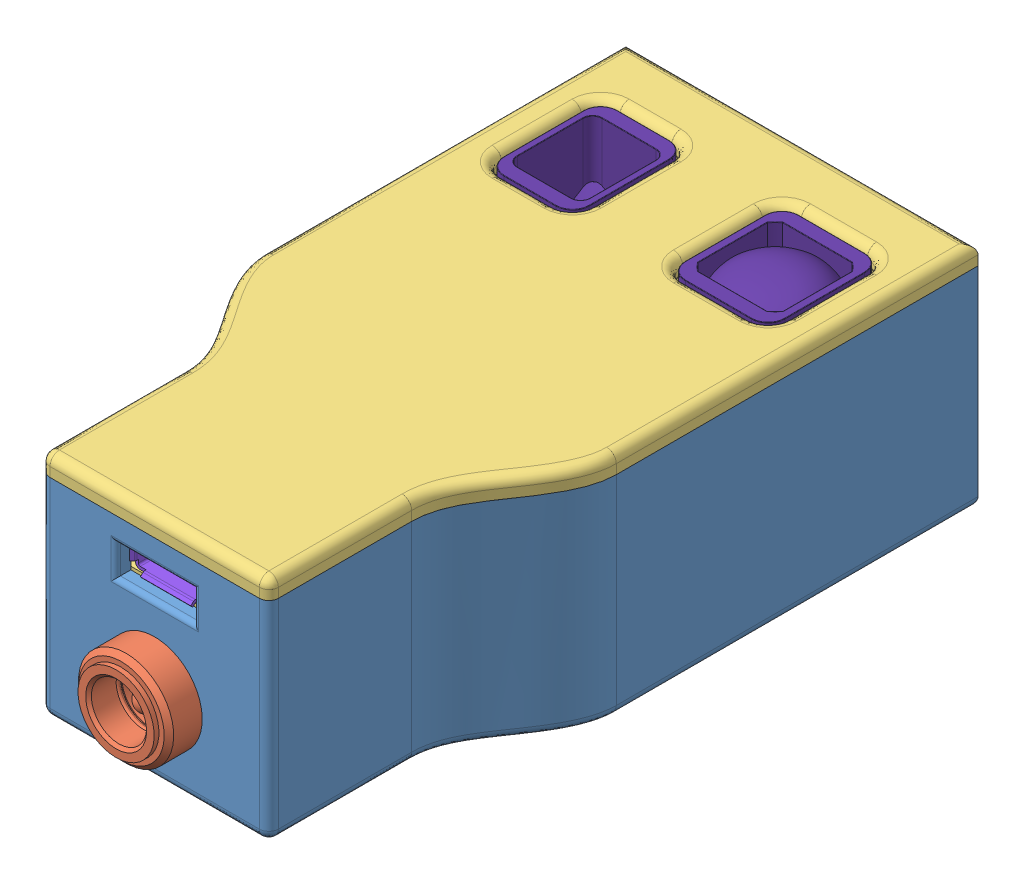
SolidWorks assembly mcu_enclosure, configuration Default. Lengths in mm.
Overall size (39.22 24.22 78.62).
37 component instances, 23 part files, 24 mates.
Components (placement in the parent):
- mcu_enclosure-1: mcu_enclosure [Default] at origin size (38.82 22.11 68)
- Lumberg_1614_10-1: Lumberg_1614_10 [Default] at (0 6 0) x (0 -1 0) z (0 0 1) size (10 10 17.01)
  - Lumberg_1614_10.stp-1: Lumberg_1614_10.stp [Default] at (0.8468 0.2582 0) size (13.42 14.23 17.01)
    - ID_1.stp-1: ID_1.stp [Default] at (-0.8468 -0.2582 0) size (10 10 17.01)
    - ID_1-0.stp-1: ID_1-0.stp [Default] at (-0.8365 -0.3028 -2.0087) x (-0.358368 0.93358 0) z (0 0 1) size (11.4 10 2.51) (hidden)
- 3800 ItsyBitsy M4-1: 3800 ItsyBitsy M4 [Default] at (8.89 13 -1.6) x (0 0 -1) z (0 1 0) size (36.02 17.78 4.34)
  - 3800-ItsyBitsy-M4.step-1: 3800-ItsyBitsy-M4.step [Default] at origin size (36.02 17.78 4.34)
    - PCB Component.step-1: PCB Component.step [Default] at origin size (36.02 17.78 4.34)
      - Board.step-1: Board.step [Default] at origin size (35.56 17.78 1.57)
      - 10_X_B5F.step-1: 10_X_B5F.step [Default] at (12.578 13.375 1.57) size (2 1.25 1)
      - 10_X_B5F.step-2: 10_X_B5F.step [Default] at (8.449 4.176 1.57) x (-1 0 0) z (0 0 1) size (2 1.25 1)
      - 100k.step-1: 100k.step [Default] at (11.447 10.782 1.57) x (0 1 0) z (0 0 1) size (1.6 0.9 0.8)
      - 100k.step-2: 100k.step [Default] at (6.768 7.163 1.57) x (0 1 0) z (0 0 1) size (1.6 0.9 0.8)
      - 100k.step-3: 100k.step [Default] at (29.21 13.78 1.57) size (1.6 0.9 0.8)
      - 100k.step-4: 100k.step [Default] at (28.321 8.318 1.57) x (0 1 0) z (0 0 1) size (1.6 0.9 0.8)
      - 100k.step-5: 100k.step [Default] at (9.144 10.033 1.57) x (-1 0 0) z (0 0 1) size (1.6 0.9 0.8)
      - 100k.step-6: 100k.step [Default] at (26.035 9.208 1.57) x (-1 0 0) z (0 0 1) size (1.6 0.9 0.8)
      - RED.step-1: RED.step [Default] at (31.536 13.376 1.57) x (-1 0 0) z (0 0 1) size (1.25 2.02 1.1)
      - SPST_TACT-KMR2.step-1: SPST_TACT-KMR2.step [Default] at (30.48 9.017 1.57) x (0 -1 0) z (0 0 1) size (4.6 2.8 1.94)
      - microUSB.step-1: microUSB.step [Default] at (4.445 8.89 1.57) x (0 -1 0) z (0 0 1) size (8.8 5.6 3)
      - AP2112K-3.3.step-1: AP2112K-3.3.step [Default] at (9.271 7.239 1.57) x (-1 0 0) z (0 0 1) size (3 3 1.4)
      - 74HCT1G125DBV.step-1: 74HCT1G125DBV.step [Default] at (24.066 13.081 1.57) x (0 1 0) z (0 0 1) size (3 3 1.4)
      - MBR120.step-1: MBR120.step [Default] at (8.572 13.462 1.57) x (-1 0 0) z (0 0 1) size (3.6 1.4 1.35)
      - MBR120.step-2: MBR120.step [Default] at (8.572 11.684 1.57) x (-1 0 0) z (0 0 1) size (3.6 1.4 1.35)
      - AP102-2020.step-1: AP102-2020.step [Default] at (12.065 4.826 1.57) size (2 2 0.9)
      - GD25x16.step-1: GD25x16.step [Default] at (26.289 5.144 1.57) x (0 -1 0) z (0 0 1) size (3 2 0.8)
      - ATSAMD51G_TQFN48.step-1: ATSAMD51G_TQFN48.step [Default] at (19.177 7.938 1.57) size (7 7 1)
      - 10uF.step-1: 10uF.step [Default] at (13.272 10.224 1.57) x (0 1 0) z (0 0 1) size (2 1.25 0.85)
      - 1uF.step-1: 1uF.step [Default] at (29.02 3.874 1.57) size (1.6 0.9 0.8)
      - 1uF.step-2: 1uF.step [Default] at (30.48 4.89 1.57) x (-1 0 0) z (0 0 1) size (1.6 0.9 0.8)
      - 1uF.step-3: 1uF.step [Default] at (30.48 5.906 1.57) size (1.6 0.9 0.8)
- GP2Y0A02YK0F SHARP_edited-1: GP2Y0A02YK0F SHARP_edited [Default] at (0 0 -55.65) x (1 0 0) z (0 1 0) size (30.02 18.9 21.6)
- 1119 12mm-TactileSwitch-1: 1119 12mm-TactileSwitch [Default] at (-13.15 10 -37) x (0 0 -1) z (0 1 0) size (12.91 8.96 12)
- ELCO_8x15mm-1: ELCO_8x15mm [Default] at (0 5.9842 -17.4502) x (-1 0 0) z (0 -1 0) size (8 20 8)
- LED_cables-1: LED_cables [Default] at (0 -1 -74.6) x (1 0 0) z (0 1 0) size (17.6 30 16.6)
- mcu_enclosure_lid-1: mcu_enclosure_lid [Default] at (0 20 0) x (-1 0 0) z (0 0 1) size (38.82 20.11 68)
- DIN EN ISO 7046-1 - M3 x 8 - Z - 8N-1: DIN EN ISO 7046-1 - M3 x 8 - Z - 8N [DIN EN ISO 7046-1 - M3 x 8 - Z - 8N] at (0 -1.65 -39.988) x (0 1 0) z (-0.613802 0 -0.78946) size (8 5.5 5.5)
Mates (geometry in assembly coordinates):
- Concentric1: concentric aligned: cylinder of mcu_enclosure-1 through (0 6 -68.001) axis (0 0 1) radius 4.05; cylinder of Lumberg_1614_10-1/Lumberg_1614_10.stp-1/ID_1.stp-1 through (0 6 0) axis (0 0 1) radius 5
- Coincident1: coincident anti-aligned: plane of mcu_enclosure-1 through (0 -2 0) normal (0 0 1); plane of Lumberg_1614_10-1/Lumberg_1614_10.stp-1/ID_1.stp-1 through (0 6 0) normal (0 0 -1)
- Parallel1: parallel anti-aligned: plane of Lumberg_1614_10-1 through (0 6 0) normal (0 -1 0)
- Coincident2: coincident aligned: plane of 3800 ItsyBitsy M4-1 through (0 13 -1.6) normal (1 0 0)
- Parallel3: parallel aligned: plane of 3800 ItsyBitsy M4-1 through (8.89 13 -1.6) normal (0 1 0)
- Coincident6: coincident aligned: plane of mcu_enclosure-1 through (0 20 -1.6) normal (0 0 -1); plane of 3800 ItsyBitsy M4-1 through (8.89 13 -1.6) normal (0 0 -1)
- Coincident7: coincident anti-aligned: plane of mcu_enclosure-1 through (-15.25 0 -22.5) normal (0 1 0); plane of GP2Y0A02YK0F SHARP_edited-1 through (-18.5 0 -55.65) normal (0 -1 0)
- Coincident8: coincident aligned: plane of GP2Y0A02YK0F SHARP_edited-1 through (0 0 -55.65) normal (1 0 0)
- Coincident9: coincident anti-aligned: plane of mcu_enclosure-1 through (0 0 -55.65) normal (0 0 1); plane of GP2Y0A02YK0F SHARP_edited-1 through (0 0 -55.65) normal (0 0 -1)
- Parallel4: parallel aligned: plane of assembly through (0 0 0) normal (0 1 0); plane of 1119 12mm-TactileSwitch-1 through (-13.15 10 -37) normal (0 1 0)
- Coincident14: coincident anti-aligned: plane of mcu_enclosure-1 through (-16.9 20 0) normal (1 0 0); plane of 1119 12mm-TactileSwitch-1 through (-16.9 5.9142 -41.0858) normal (-1 0 0)
- Parallel10: parallel anti-aligned: plane of ELCO_8x15mm-1 through (0 5.9842 -17.4502) normal (0 -1 0)
- Parallel11: parallel anti-aligned: plane of ELCO_8x15mm-1 through (0 5.9842 -17.4502) normal (0 0 -1)
- Concentric2: concentric aligned: cylinder of mcu_enclosure-1 through (18.501 10 -37) axis (-1 0 0) radius 3.75; cylinder of 1119 12mm-TactileSwitch-1 through (-16.65 10 -37) axis (-1 0 0) radius 3.55
- Coincident17: coincident aligned: plane of LED_cables-1 through (0 -1 -74.6) normal (1 0 0)
- Distance1: distance = 1 mm aligned: plane of LED_cables-1 through (0 -1 -74.6) normal (0 1 0)
- Distance2: distance = 6.6 mm aligned: plane of LED_cables-1 through (0 -1 -74.6) normal (0 0 -1); plane of mcu_enclosure-1 through (-18.5 -2 -68) normal (0 0 -1)
- Coincident20: coincident anti-aligned: plane of mcu_enclosure-1 through (-4.1 13 -4.6) normal (0 1 0); plane of 3800 ItsyBitsy M4-1/3800-ItsyBitsy-M4.step-1/PCB Component.step-1/Board.step-1 through (0 13 -19.38) normal (0 -1 0)
- Coincident21: coincident anti-aligned: plane of mcu_enclosure-1 through (0 20 0) normal (0 1 0); plane of mcu_enclosure_lid-1 through (15.25 20 -22.5) normal (0 -1 0)
- Coincident22: coincident aligned: plane of mcu_enclosure-1 through (0 -2 0) normal (0 0 1); plane of mcu_enclosure_lid-1 through (0 20 0) normal (0 0 1)
- Coincident23: coincident anti-aligned: plane of mcu_enclosure_lid-1 through (0 20 0) normal (-1 0 0)
- Coincident24: coincident anti-aligned: plane of ELCO_8x15mm-1 through (0 5.9842 -17.4502) normal (-1 0 0)
- Concentric3: concentric anti-aligned: circle of mcu_enclosure_lid-1; cylinder of DIN EN ISO 7046-1 - M3 x 8 - Z - 8N-1 through (0 -8 -39.988) axis (0 -1 0) radius 1.5
- Coincident25: coincident aligned: cone of mcu_enclosure-1 through (0 -2 -39.988) axis (0 1 0); cone of DIN EN ISO 7046-1 - M3 x 8 - Z - 8N-1 through (0 -1.25 -39.988) axis (0 1 0)
